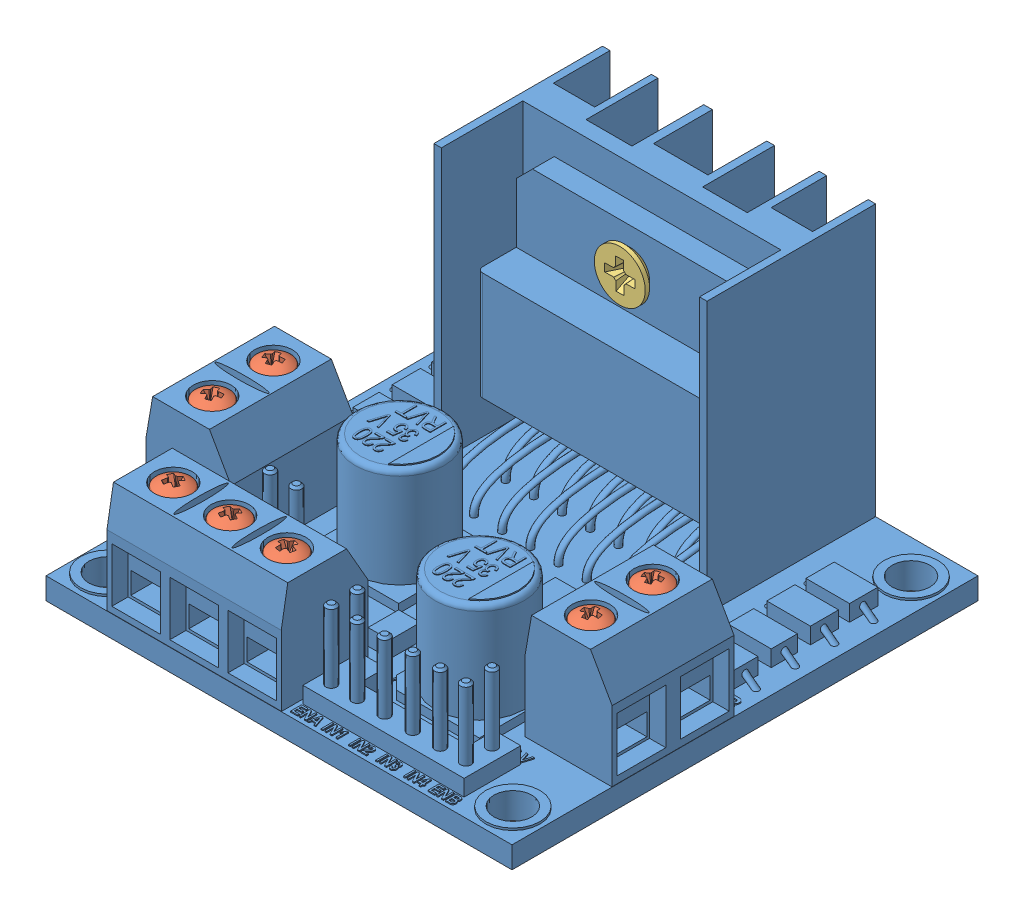
SolidWorks assembly L298N Stepper Motor Driver (Red), configuration Default. Lengths in mm.
Overall size (43 28.01 43).
9 component instances, 3 part files, 16 mates.
Components (placement in the parent):
- L298N Stepper Motor Driver (Red)-1: L298N Stepper Motor Driver (Red) [Default] at (-89.3884 -13.295 48.5108) size (43 28.01 43)
- pan head cross recess screw_iso-1: pan head cross recess screw_iso [ISO 7045 - M1.6 x 4 - Z - 4N] at (-72.5884 -0.995 52.3243) x (0 -1 0) z (0.332966 0 0.942939) size (5.27 3.2 3.2)
- pan head cross recess screw_iso-3: pan head cross recess screw_iso [ISO 7045 - M1.6 x 4 - Z - 4N] at (-91.9801 -0.995 66.6875) x (0 -1 0) z (-0.208825 0 0.977953) size (5.27 3.2 3.2)
- pan head cross recess screw_iso-4: pan head cross recess screw_iso [ISO 7045 - M1.6 x 4 - Z - 4N] at (-97.2219 -0.995 66.6875) x (0 -1 0) z (-0.893472 0 -0.449119) size (5.27 3.2 3.2)
- pan head cross recess screw_iso-5: pan head cross recess screw_iso [ISO 7045 - M1.6 x 4 - Z - 4N] at (-102.4637 -0.995 66.6875) x (0 -1 0) z (-0.477141 0 0.878827) size (5.27 3.2 3.2)
- pan head cross recess screw_iso-6: pan head cross recess screw_iso [ISO 7045 - M1.6 x 4 - Z - 4N] at (-107.5884 -0.995 57.9688) x (0 -1 0) z (0.396742 0 0.91793) size (5.27 3.2 3.2)
- pan head cross recess screw_iso-7: pan head cross recess screw_iso [ISO 7045 - M1.6 x 4 - Z - 4N] at (-107.5884 -0.995 52.3243) x (0 -1 0) z (0.339075 0 0.940759) size (5.27 3.2 3.2)
- pan head cross recess screw_iso-8: pan head cross recess screw_iso [ISO 7045 - M1.6 x 4 - Z - 4N] at (-72.5884 -0.995 58.0188) x (0 -1 0) z (-0.984368 0 0.176126) size (5.27 3.2 3.2)
- countersunk flat head cross recess screw_iso-2: countersunk flat head cross recess screw_iso [ISO 7046-1 - M2.5 x 3 - Z - 3N] at (-89.8922 7.205 38.0625) x (0 0 -1) z (0.999801 0.019932 0) size (3 4.7 4.7)
Mates (geometry in assembly coordinates):
- Concentric1: concentric aligned: cylinder of L298N Stepper Motor Driver (Red)-1 through (-72.5884 -6.295 52.3243) axis (0 1 0) radius 1.75; cylinder of pan head cross recess screw_iso-1 through (-72.5884 24.405 52.3243) axis (0 1 0) radius 1.6
- Concentric3: concentric aligned: cylinder of L298N Stepper Motor Driver (Red)-1 through (-91.9801 -6.295 66.6875) axis (0 1 0) radius 1.75; cylinder of pan head cross recess screw_iso-3 through (-91.9801 24.405 66.6875) axis (0 1 0) radius 1.6
- Concentric4: concentric aligned: cylinder of L298N Stepper Motor Driver (Red)-1 through (-97.2219 -6.295 66.6875) axis (0 1 0) radius 1.75; cylinder of pan head cross recess screw_iso-4 through (-97.2219 24.405 66.6875) axis (0 1 0) radius 1.6
- Concentric5: concentric aligned: cylinder of L298N Stepper Motor Driver (Red)-1 through (-102.4637 -6.295 66.6875) axis (0 1 0) radius 1.75; cylinder of pan head cross recess screw_iso-5 through (-102.4637 24.405 66.6875) axis (0 1 0) radius 1.6
- Concentric6: concentric aligned: cylinder of L298N Stepper Motor Driver (Red)-1 through (-107.5884 -6.295 57.9688) axis (0 1 0) radius 1.75; cylinder of pan head cross recess screw_iso-6 through (-107.5884 24.405 57.9688) axis (0 1 0) radius 1.6
- Concentric7: concentric aligned: cylinder of L298N Stepper Motor Driver (Red)-1 through (-107.5884 -6.295 52.3243) axis (0 1 0) radius 1.75; cylinder of pan head cross recess screw_iso-7 through (-107.5884 24.405 52.3243) axis (0 1 0) radius 1.6
- Concentric8: concentric aligned: cylinder of L298N Stepper Motor Driver (Red)-1 through (-72.5884 -6.295 58.0188) axis (0 1 0) radius 1.75; cylinder of pan head cross recess screw_iso-8 through (-72.5884 24.405 58.0188) axis (0 1 0) radius 1.6
- Coincident11: coincident anti-aligned: plane of L298N Stepper Motor Driver (Red)-1 through (-72.5884 -6.295 52.3243) normal (0 1 0); plane of pan head cross recess screw_iso-1 through (-71.834 -6.295 52.0579) normal (0 -1 0)
- Coincident12: coincident anti-aligned: plane of L298N Stepper Motor Driver (Red)-1 through (-72.5884 -6.295 58.0188) normal (0 1 0); plane of pan head cross recess screw_iso-8 through (-72.4475 -6.295 58.8063) normal (0 -1 0)
- Coincident13: coincident anti-aligned: plane of L298N Stepper Motor Driver (Red)-1 through (-91.9801 -6.295 66.6875) normal (0 1 0); plane of pan head cross recess screw_iso-3 through (-91.1978 -6.295 66.8545) normal (0 -1 0)
- Coincident14: coincident anti-aligned: plane of L298N Stepper Motor Driver (Red)-1 through (-97.2219 -6.295 66.6875) normal (0 1 0); plane of pan head cross recess screw_iso-4 through (-97.5812 -6.295 67.4023) normal (0 -1 0)
- Coincident15: coincident anti-aligned: plane of L298N Stepper Motor Driver (Red)-1 through (-102.4637 -6.295 66.6875) normal (0 1 0); plane of pan head cross recess screw_iso-5 through (-101.7606 -6.295 67.0692) normal (0 -1 0)
- Coincident16: coincident anti-aligned: plane of L298N Stepper Motor Driver (Red)-1 through (-107.5884 -6.295 57.9688) normal (0 1 0); plane of pan head cross recess screw_iso-6 through (-106.854 -6.295 57.6514) normal (0 -1 0)
- Coincident17: coincident anti-aligned: plane of L298N Stepper Motor Driver (Red)-1 through (-107.5884 -6.295 52.3243) normal (0 1 0); plane of pan head cross recess screw_iso-7 through (-106.8358 -6.295 52.053) normal (0 -1 0)
- Concentric13: concentric aligned: cylinder of L298N Stepper Motor Driver (Red)-1 through (-89.8922 7.205 30.1127) axis (0 0 1) radius 1.75; cylinder of countersunk flat head cross recess screw_iso-2 through (-89.8922 7.205 44.4125) axis (0 0 1) radius 1.25
- Coincident20: coincident anti-aligned: plane of L298N Stepper Motor Driver (Red)-1 through (-101.8441 13.705 35.0625) normal (0 0 1); plane of countersunk flat head cross recess screw_iso-2 through (-89.9172 8.4548 35.0625) normal (0 0 -1)
